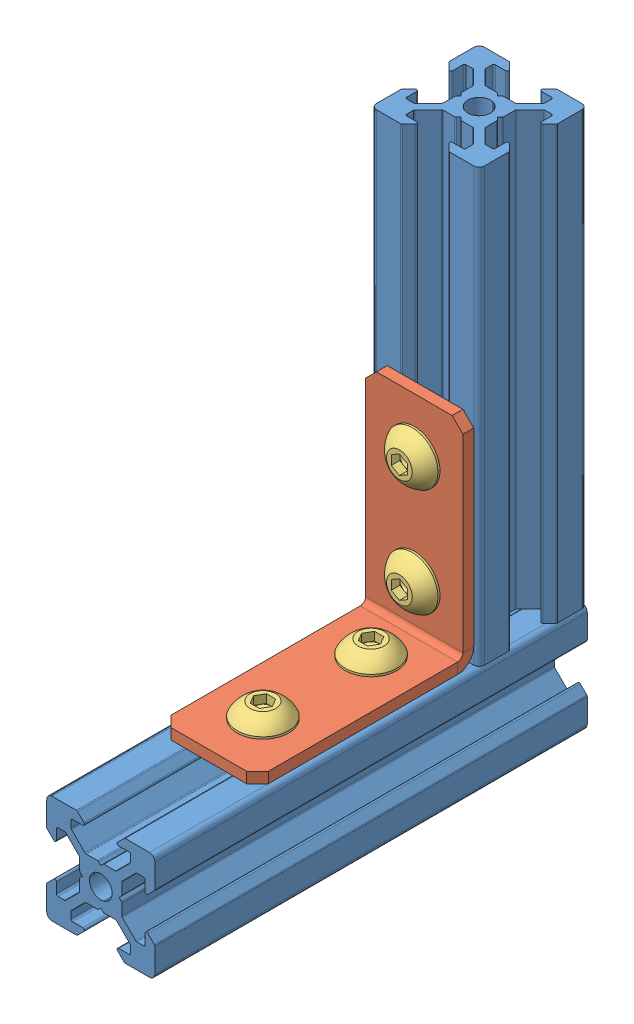
SolidWorks assembly Уголок 20 серия 1х4 40х40х18х2 СБ, configuration По умолчанию. Lengths in mm.
Overall size (20 100 80).
7 component instances, 3 part files, 14 mates.
Components (placement in the parent):
- 2020100-1: 2020100 [По умолчанию] at origin size (20 20 80)
- 2020100-2: 2020100 [По умолчанию] at (0 10 10) x (1 0 0) z (0 1 0) size (20 20 80)
- Уголок 20 серия 1х4 40х40х18х2-1: Уголок 20 серия 1х4 40х40х18х2 [По умолчанию] at (0 10 20) size (18 40 40)
- socket button head screw_iso-5: socket button head screw_iso [ISO 7380 - M5 x 10 - 10N] at (0 40 24.75) x (0 0 -1) z (1 0 0) size (12.75 9.5 9.5)
- socket button head screw_iso-6: socket button head screw_iso [ISO 7380 - M5 x 10 - 10N] at (0 20 24.75) x (0 0 -1) z (1 0 0) size (12.75 9.5 9.5)
- socket button head screw_iso-7: socket button head screw_iso [ISO 7380 - M5 x 10 - 10N] at (0 14.75 30) x (0 -1 0) z (0 0 1) size (12.75 9.5 9.5)
- socket button head screw_iso-8: socket button head screw_iso [ISO 7380 - M5 x 10 - 10N] at (0 14.75 50) x (0 -1 0) z (0 0 1) size (12.75 9.5 9.5)
Mates (geometry in assembly coordinates):
- Совпадение1: coincident aligned: plane of 2020100-1 through (10 10 80) normal (1 0 0); plane of 2020100-2 through (10 90 20) normal (1 0 0)
- Совпадение2: coincident anti-aligned: plane of 2020100-1 through (10 10 80) normal (0 1 0); plane of 2020100-2 through (0 10 10) normal (0 -1 0)
- Совпадение3: coincident anti-aligned: plane of 2020100-1 through (-10 10 80) normal (0 1 0); plane of Уголок 20 серия 1х4 40х40х18х2-1 through (0 10 20) normal (0 -1 0)
- Совпадение4: coincident anti-aligned: plane of 2020100-2 through (-10 90 20) normal (0 0 1); plane of Уголок 20 серия 1х4 40х40х18х2-1 through (0 10 20) normal (0 0 -1)
- Совпадение5: coincident aligned: plane of 2020100-1 through (0 0 0) normal (0 0 -1); plane of 2020100-2 through (-10 90 0) normal (0 0 -1)
- Расстояние1: distance = 1 mm aligned: plane of 2020100-1 through (10 10 80) normal (1 0 0); plane of Уголок 20 серия 1х4 40х40х18х2-1 through (9 10 60) normal (1 0 0)
- Концентричный1: concentric aligned: cylinder of Уголок 20 серия 1х4 40х40х18х2-1 through (0 40 22) axis (0 0 1) radius 2.75; cylinder of socket button head screw_iso-5 through (0 40 24.75) axis (0 0 1) radius 4.75
- Совпадение6: coincident anti-aligned: plane of Уголок 20 серия 1х4 40х40х18х2-1 through (0 10 22) normal (0 0 1); plane of socket button head screw_iso-5 through (0 42.5 22) normal (0 0 -1)
- Концентричный2: concentric aligned: cylinder of Уголок 20 серия 1х4 40х40х18х2-1 through (0 20 22) axis (0 0 1) radius 2.75; cylinder of socket button head screw_iso-6 through (0 20 24.75) axis (0 0 1) radius 4.75
- Совпадение7: coincident anti-aligned: plane of Уголок 20 серия 1х4 40х40х18х2-1 through (0 10 22) normal (0 0 1); plane of socket button head screw_iso-6 through (0 22.5 22) normal (0 0 -1)
- Концентричный3: concentric aligned: cylinder of Уголок 20 серия 1х4 40х40х18х2-1 through (0 12 30) axis (0 1 0) radius 2.75; cylinder of socket button head screw_iso-7 through (0 14.75 30) axis (0 1 0) radius 4.75
- Совпадение8: coincident anti-aligned: plane of Уголок 20 серия 1х4 40х40х18х2-1 through (0 12 20) normal (0 1 0); plane of socket button head screw_iso-7 through (2.5 12 30) normal (0 -1 0)
- Концентричный4: concentric aligned: cylinder of Уголок 20 серия 1х4 40х40х18х2-1 through (0 12 50) axis (0 1 0) radius 2.75; cylinder of socket button head screw_iso-8 through (0 14.75 50) axis (0 1 0) radius 4.75
- Совпадение9: coincident anti-aligned: plane of Уголок 20 серия 1х4 40х40х18х2-1 through (0 12 20) normal (0 1 0); plane of socket button head screw_iso-8 through (2.5 12 50) normal (0 -1 0)
